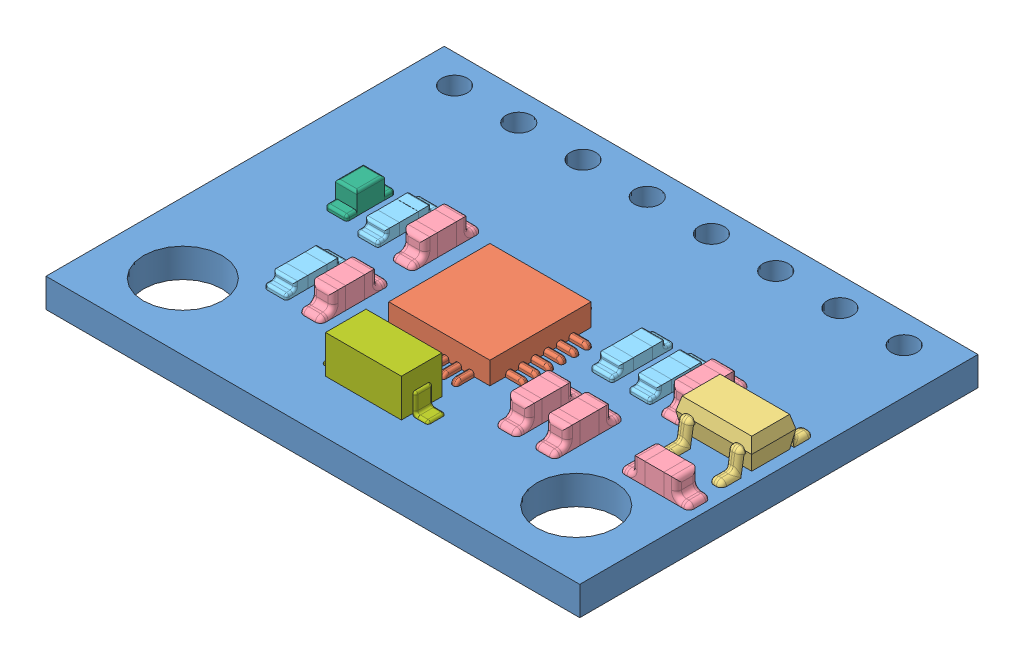
SolidWorks assembly MPU 6050 IMU, configuration Default. Lengths in mm.
Overall size (21.11 2.74 15.75).
15 component instances, 7 part files, 30 mates.
Components (placement in the parent):
- Base-1: Base [Default] at (7.2489 10.9584 16.5726) size (21.11 1.14 15.75)
- sensor chip-1: sensor chip [Default] at (7.2489 11.5499 17.4466) size (5.4 0.9 5.4)
- S2NH chip-1: S2NH chip [Default] at (16.1026 12.3799 16.5726) size (3 1.35 3.65)
- Resistor small-3: Resistor small [Default] at (16.1026 11.5314 19.3726) size (2.75 0.99 1)
- Resistor small-4: Resistor small [Default] at (13.9776 11.5314 15.6976) x (0 0 -1) z (1 0 0) size (2.75 0.99 1)
- Resistor small black-3: Resistor small black [Default] at (12.6276 11.5299 15.6976) x (0 0 1) z (-1 0 0) size (2.45 0.6 1.02)
- Resistor small black-4: Resistor small black [Default] at (11.1276 11.5299 15.6976) x (0 0 1) z (-1 0 0) size (2.45 0.6 1.02)
- Resistor small-5: Resistor small [Default] at (12.6276 11.5314 19.3216) x (0 0 -1) z (1 0 0) size (2.75 0.99 1)
- Resistor small-6: Resistor small [Default] at (11.1276 11.5314 19.3216) x (0 0 -1) z (1 0 0) size (2.75 0.99 1)
- Resistor small-7: Resistor small [Default] at (3.3702 11.5314 19.3216) x (0 0 -1) z (1 0 0) size (2.75 0.99 1)
- Resistor small black-5: Resistor small black [Default] at (1.8702 11.5299 15.6972) x (0 0 -1) z (1 0 0) size (2.45 0.6 1.02)
- Resistor small-8: Resistor small [Default] at (3.3702 11.5314 15.6976) x (0 0 1) z (-1 0 0) size (2.75 0.99 1)
- Small LED-1: Small LED [Default] at (0.3652 11.5299 15.6976) size (0.85 0.84 1.9)
- Resistor small black-6: Resistor small black [Default] at (1.8702 11.5299 19.3216) x (0 0 1) z (-1 0 0) size (2.45 0.6 1.02)
- Resistor black-1: Resistor black [Default] at (7.2489 12.3799 21.6466) size (4.2 1.6 1.6)
Mates (geometry in assembly coordinates):
- Coincident6: coincident anti-aligned: plane of Base-1 through (7.2489 11.5299 16.5726) normal (0 1 0); plane of sensor chip-1 through (7.2489 11.5299 17.4466) normal (0 -1 0)
- Coincident7: coincident aligned: plane of Base-1 through (7.2489 10.9584 16.5726) normal (1 0 0); plane of sensor chip-1 through (7.2489 11.5499 17.4466) normal (1 0 0)
- Distance1: distance = 5 mm aligned: plane of sensor chip-1 through (5.2489 12.4299 19.4466) normal (0 0 1); plane of Base-1 through (-3.3048 11.5299 24.4466) normal (0 0 1)
- Coincident8: coincident anti-aligned: plane of Base-1 through (7.2489 11.5299 16.5726) normal (0 1 0); plane of S2NH chip-1 through (16.1026 11.5299 16.5726) normal (0 -1 0)
- Coincident9: coincident aligned: plane of Base-1 through (7.2489 10.9584 16.5726) normal (0 0 1); plane of S2NH chip-1 through (16.1026 12.3799 16.5726) normal (0 0 1)
- Distance2: distance = 0.2 mm: line of S2NH chip-1 through (17.6026 12.3799 17.4476) axis (0 0 -1); plane of Base-1 through (17.8026 11.5299 24.4466) normal (1 0 0)
- Coincident19: coincident anti-aligned: plane of Base-1 through (7.2489 11.5299 16.5726) normal (0 1 0); plane of Resistor small-3 through (16.9776 11.5299 19.8026) normal (0 -1 0)
- Coincident20: coincident aligned: plane of S2NH chip-1 through (16.1026 12.3799 16.5726) normal (1 0 0); plane of Resistor small-3 through (16.1026 11.5314 19.3726) normal (1 0 0)
- Distance5: distance = 1.5 mm: line of S2NH chip-1 through (15.3258 12.3799 17.4476) axis (1 0 0); plane of Resistor small-3 through (16.4776 11.5314 18.9476) normal (0 0 -1)
- Coincident22: coincident anti-aligned: plane of Base-1 through (7.2489 11.5299 16.5726) normal (0 1 0); plane of Resistor small-4 through (14.4076 11.5299 14.8226) normal (0 -1 0)
- Coincident24: coincident: line of S2NH chip-1 through (16.8794 12.3799 15.6976) axis (-1 0 0); plane of Resistor small-4 through (13.9776 11.5314 15.6976) normal (0 0 -1)
- Distance6: distance = 0.2 mm: plane of Resistor small-4 through (14.4026 11.5314 15.3226) normal (1 0 0); line of S2NH chip-1 through (14.6026 12.3799 15.6976) axis (0 0 1)
- Coincident26: coincident anti-aligned: plane of Base-1 through (7.2489 11.5299 16.5726) normal (0 1 0); plane of Resistor small black-3 through (12.2026 11.5299 16.0726) normal (0 -1 0)
- Coincident28: coincident anti-aligned: plane of Resistor small-4 through (13.9776 11.5314 15.6976) normal (0 0 -1); plane of Resistor small black-3 through (12.6276 11.5299 15.6976) normal (0 0 1)
- Distance7: distance = 0.5 mm anti-aligned: plane of Resistor small-4 through (13.5526 11.5314 15.3226) normal (-1 0 0); plane of Resistor small black-3 through (13.0526 11.5299 16.0726) normal (1 0 0)
- Coincident30: coincident anti-aligned: plane of Base-1 through (7.2489 11.5299 16.5726) normal (0 1 0); plane of Resistor small-5 through (13.0576 11.5299 18.4466) normal (0 -1 0)
- Coincident31: coincident anti-aligned: plane of Resistor small black-3 through (12.6276 11.5299 15.6976) normal (-1 0 0); plane of Resistor small-5 through (12.6276 11.5314 19.3216) normal (1 0 0)
- Distance8: distance = 4.25 mm aligned: plane of Resistor small-5 through (12.6276 11.5314 20.1966) normal (0 0 1); plane of Base-1 through (-3.3048 11.5299 24.4466) normal (0 0 1)
- Coincident33: coincident anti-aligned: plane of Base-1 through (7.2489 11.5299 16.5726) normal (0 1 0); plane of Resistor small-8 through (2.9402 11.5299 14.8226) normal (0 -1 0)
- Coincident34: coincident anti-aligned: plane of Resistor small-7 through (3.3702 11.5314 19.3216) normal (1 0 0); plane of Resistor small-8 through (3.3702 11.5314 15.6976) normal (-1 0 0)
- Coincident36: coincident: line of S2NH chip-1 through (15.8794 12.3799 15.6976) axis (-1 0 0); plane of Resistor small-8 through (3.3702 11.5314 15.6976) normal (0 0 1)
- Coincident37: coincident anti-aligned: plane of Base-1 through (7.2489 11.5299 16.5726) normal (0 1 0); plane of Small LED-1 through (0.3652 11.5299 15.6976) normal (0 -1 0)
- Coincident38: coincident: line of S2NH chip-1 through (15.8794 12.3799 15.6976) axis (-1 0 0); plane of Small LED-1 through (0.3652 11.5299 15.6976) normal (0 0 1)
- Distance9: distance = 1.5 mm aligned: plane of Small LED-1 through (-0.0548 12.3699 16.2476) normal (-1 0 0); plane of Resistor small black-5 through (1.4452 11.5299 15.3222) normal (-1 0 0)
- Coincident40: coincident anti-aligned: plane of Base-1 through (7.2489 11.5299 16.5726) normal (0 1 0); plane of Resistor small black-6 through (1.4452 11.5299 19.6966) normal (0 -1 0)
- Coincident41: coincident anti-aligned: plane of Resistor small black-5 through (1.8702 11.5299 15.6972) normal (1 0 0); plane of Resistor small black-6 through (1.8702 11.5299 19.3216) normal (-1 0 0)
- Coincident42: coincident anti-aligned: plane of Resistor small-7 through (3.3702 11.5314 19.3216) normal (0 0 -1); plane of Resistor small black-6 through (1.8702 11.5299 19.3216) normal (0 0 1)
- Coincident43: coincident anti-aligned: plane of Base-1 through (7.2489 11.5299 16.5726) normal (0 1 0); plane of Resistor black-1 through (5.6489 11.5299 21.9966) normal (0 -1 0)
- Coincident44: coincident aligned: plane of Base-1 through (7.2489 10.9584 16.5726) normal (1 0 0); plane of Resistor black-1 through (7.2489 12.3799 21.6466) normal (1 0 0)
- Distance10: distance = 2 mm aligned: plane of Resistor black-1 through (5.7489 13.1299 22.4466) normal (0 0 1); plane of Base-1 through (-3.3048 11.5299 24.4466) normal (0 0 1)
